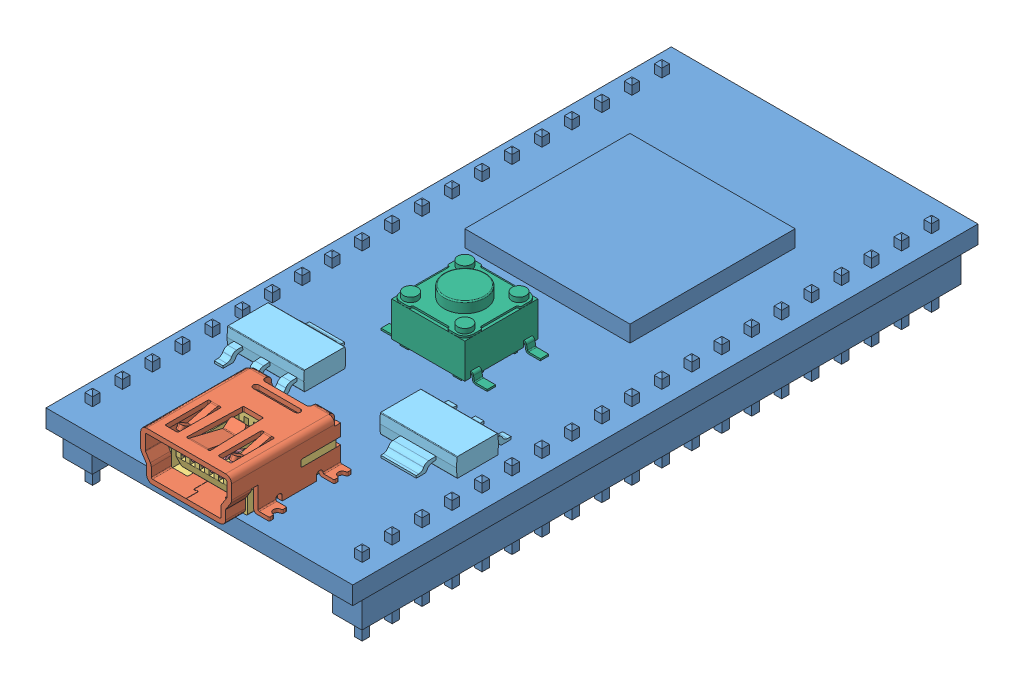
SolidWorks assembly mbed_NXP_LPC1768, configuration Default. Lengths in mm.
Overall size (26 10.32 54.13).
12 component instances, 6 part files, 15 mates.
Components (placement in the parent):
- mbed_NXP_LPC1768-1: mbed_NXP_LPC1768 [Default] at origin size (26 7.42 53)
- usb_mini_b-1: usb_mini_b [Default] at (0 3.474 23) x (-1 0 0) z (0 -1 0) size (9.6 9.25 4.91)
  - Shielding-1: Shielding [Default] at origin size (9.6 9.25 4.01)
  - Insulator-1: Insulator [Default] at (0 2.75 0.2) size (7.7 7.5 4.5)
  - Pin_1-1: Pin_1 [Default] at (-1.6 2.225 0.575) size (0.4 7.85 3.02)
  - Pin_1-2: Pin_1 [Default] at (-0.8 2.225 0.575) size (0.4 7.85 3.02)
  - Pin_1-3: Pin_1 [Default] at (0 2.225 0.575) size (0.4 7.85 3.02)
  - Pin_1-4: Pin_1 [Default] at (0.8 2.225 0.575) size (0.4 7.85 3.02)
  - Pin_1-5: Pin_1 [Default] at (1.6 2.225 0.575) size (0.4 7.85 3.02)
- SOT-223-1: SOT-223 [Default] at (-6.8 -6.9808 24) x (0 0 1) z (-1 0 0) size (6.89 1.7 6.5)
- SOT-223-2: SOT-223 [Default] at (6.7 -6.9808 1.2) x (0 0 -1) z (1 0 0) size (6.89 1.7 6.5)
- Tact_Sw_SMD_6x6mm-1: Tact_Sw_SMD_6x6mm [Default] at (0 1.524 4) x (1 0 0) z (0 1 0) size (9 6.2 4.3)
Mates (geometry in assembly coordinates):
- Coincident1: coincident: plane of mbed_NXP_LPC1768-1 through (0 0 0) normal (0 0 1); plane of assembly through (0 0 0) normal (0 0 1)
- Coincident2: coincident: plane of mbed_NXP_LPC1768-1 through (0 0 0) normal (0 1 0); plane of assembly through (0 0 0) normal (0 1 0)
- Coincident3: coincident: plane of mbed_NXP_LPC1768-1 through (0 0 0) normal (1 0 0); plane of assembly through (0 0 0) normal (1 0 0)
- Coincident4: coincident: plane of mbed_NXP_LPC1768-1 through (0 1.524 0) normal (0 1 0); plane of usb_mini_b-1/Insulator-1 through (-3.45 1.524 21.725) normal (0 -1 0)
- Coincident6: coincident: plane of usb_mini_b-1/Shielding-1 through (0 3.474 23) normal (-1 0 0); plane of assembly through (0 0 0) normal (1 0 0)
- Distance2: distance = 23 mm: plane of assembly through (0 0 0) normal (0 0 1); plane of usb_mini_b-1/Shielding-1 through (0 3.474 23) normal (0 0 -1)
- Coincident9: coincident: plane of mbed_NXP_LPC1768-1 through (0 1.524 0) normal (0 1 0); plane of SOT-223-1 through (-9.7114 1.524 10.9319) normal (0 -1 0)
- Coincident10: coincident: plane of mbed_NXP_LPC1768-1 through (0 1.524 0) normal (0 1 0); plane of SOT-223-2 through (9.6114 1.524 14.2681) normal (0 -1 0)
- Distance3: distance = 6.8 mm: plane of SOT-223-1 through (-6.8 -6.9808 24) normal (-1 0 0); plane of assembly through (0 0 0) normal (1 0 0)
- Distance4: distance = 6.7 mm: plane of assembly through (0 0 0) normal (1 0 0); plane of SOT-223-2 through (6.7 -6.9808 1.2) normal (1 0 0)
- Distance5: distance = 1.2 mm: plane of SOT-223-2 through (6.7 -6.9808 1.2) normal (0 0 -1); plane of assembly through (0 0 0) normal (0 0 1)
- Distance6: distance = 24 mm: plane of assembly through (0 0 0) normal (0 0 1); plane of SOT-223-1 through (-6.8 -6.9808 24) normal (0 0 1)
- Coincident15: coincident: plane of mbed_NXP_LPC1768-1 through (0 1.524 0) normal (0 1 0); plane of Tact_Sw_SMD_6x6mm-1 through (-3.492 1.524 2.8445) normal (0 -1 0)
- Coincident16: coincident: plane of Tact_Sw_SMD_6x6mm-1 through (0 1.524 4) normal (1 0 0); plane of assembly through (0 0 0) normal (1 0 0)
- Distance7: distance = 4 mm: plane of assembly through (0 0 0) normal (0 0 1); plane of Tact_Sw_SMD_6x6mm-1 through (0 1.524 4) normal (0 0 -1)
